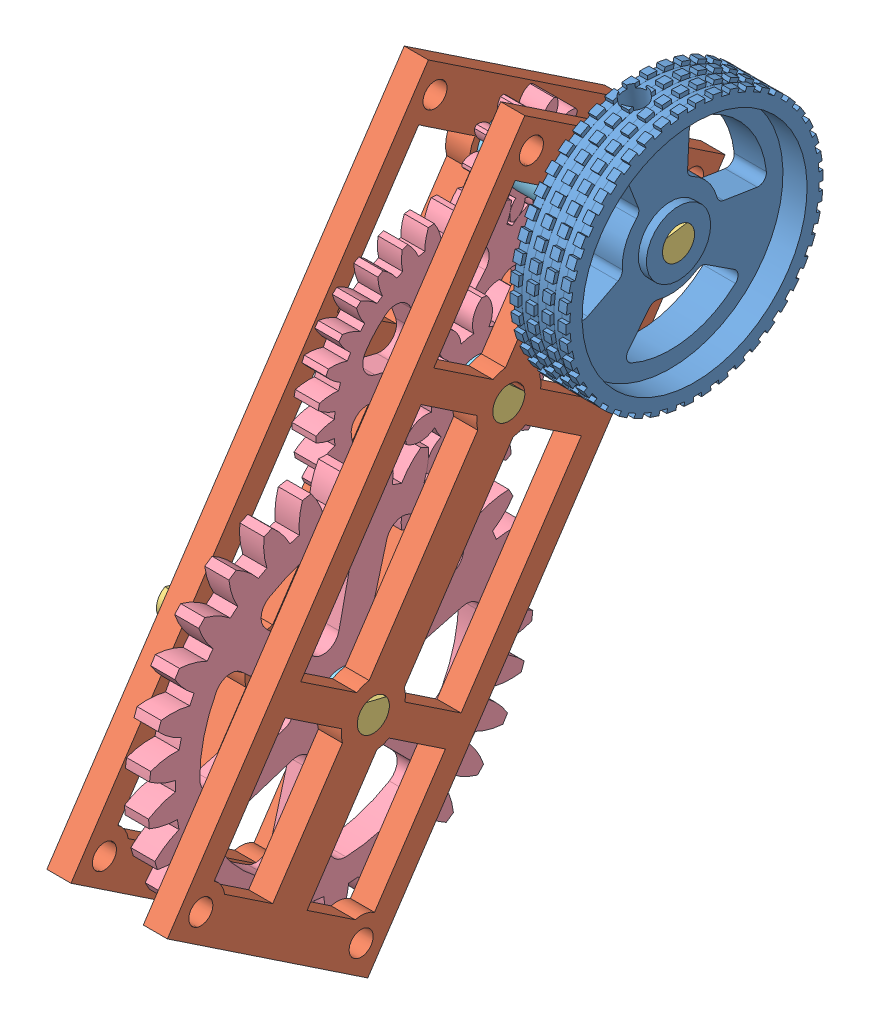
SolidWorks assembly Gearbox Assembly 2, configuration Default. Lengths in mm.
Overall size (37 89.16 75.24).
20 component instances, 5 part files, 14 mates.
Components (placement in the parent):
- knob-1: knob [Default] at (6.9201 63.2901 -12.547) x (1 0 0) z (0 -0.159161 0.987253) size (7 31.99 32)
- plate 2-1: plate 2 [Default] at (1.9201 35.0287 6.3551) x (0 -0.831219 0.555945) z (-1 0 0) size (80 30 3)
- Subassembly 1-1: Subassembly 1 [Default] at (9.8488 64.0208 -35.2482) x (0 -0.987253 -0.159161) z (-1 0 0) size (12 11.53 25)
  - axle-1: axle [25mm axle] at (-2.8918 22.5281 -2.0712) size (3.5 4 25)
  - root gear assignment-1: root gear assignment [10T 1.0Mod] at (-2.8918 22.5281 18.9288) x (-1 0 0) z (0 0 -1) size (12 11.53 3)
  - Spacer-1: Spacer [4.2-1] at (-2.8918 22.5281 18.9288) x (0.950881 0.309557 0) z (0 0 1) size (6.2 6.2 1)
  - Spacer-2: Spacer [4.2-5] at (-2.8918 22.5281 10.9288) x (-0.422504 -0.906361 0) z (0 0 1) size (6.2 6.2 5)
- Subassembly 2-1: Subassembly 2 [Default] at (-12.5765 19.149 -11.8568) x (0 0.742138 -0.670247) z (1 0 0) size (32 31.89 15)
  - root gear assignment-1: root gear assignment [30T 1.0Mod] at (13.4314 26.1825 3.4966) size (32 31.89 3)
  - root gear assignment-2: root gear assignment [10T 1.5Mod] at (13.4314 26.1825 7.4966) size (18 17.3 3)
  - axle-1: axle [15mm axle] at (13.4314 26.1825 -0.5034) x (-1 0 0) z (0 0 1) size (3.5 4 15)
  - Spacer-1: Spacer [4.2-1] at (13.4314 26.1825 10.4966) size (6.2 6.2 1)
  - Spacer-3: Spacer [4.2-1] at (13.4314 26.1825 6.4966) size (6.2 6.2 1)
  - Spacer-4: Spacer [4.2-1] at (13.4314 26.1825 2.4966) size (6.2 6.2 1)
- Subassembly3-1: Subassembly3 [Default] at (-24.9496 4.3708 -2.0102) x (0 0.971552 -0.236825) z (1 0 0) size (48 47.84 25)
  - root gear assignment-1: root gear assignment [30T 1.5Mod] at (12.467 20.9936 19.8697) size (48 47.84 3)
  - axle-1: axle [25mm axle] at (12.467 20.9936 1.8697) x (-1 0 0) z (0 0 1) size (3.5 4 25)
  - Spacer-1: Spacer [4.2-1] at (12.467 20.9936 23.8697) x (-0.923728 -0.383049 0) z (0 0 -1) size (6.2 6.2 1)
  - Spacer-2: Spacer [4.2-5] at (12.467 20.9936 14.8697) size (6.2 6.2 5)
- plate 2-2: plate 2 [Default] at (-10.0799 35.0287 6.3551) x (0 -0.831219 0.555945) z (-1 0 0) size (80 30 3)
Mates (geometry in assembly coordinates):
- Parallel1: parallel aligned: line of plate-1 through (1.9201 10.1191 41.0612) axis (0 0.831219 -0.555945); line of plate-2 through (-13.0799 10.1191 41.0612) axis (0 0.831219 -0.555945)
- Concentric3: concentric anti-aligned: cylinder of plate-1 through (1.9201 63.2901 -12.547) axis (-1 0 0) radius 2; cylinder of Subassembly 1-1/axle-1 through (-13.0799 63.2901 -12.547) axis (1 0 0) radius 2
- Concentric4: concentric anti-aligned: cylinder of Subassembly 1-1/axle-1 through (-13.0799 63.2901 -12.547) axis (1 0 0) radius 2; cylinder of plate-2 through (-10.0799 63.2901 -12.547) axis (-1 0 0) radius 2
- Coincident6: coincident aligned: plane of Subassembly 1-1/axle-1 through (-13.0799 63.2901 -12.547) normal (-1 0 0); plane of plate-2 through (-13.0799 35.0287 6.3551) normal (-1 0 0)
- Concentric5: concentric anti-aligned: cylinder of knob-1 through (6.9201 63.2901 -12.547) axis (-1 0 0) radius 2; cylinder of Subassembly 1-1/axle-1 through (-13.0799 63.2901 -12.547) axis (1 0 0) radius 2
- Coincident7: coincident aligned: plane of knob-1 through (11.9201 67.2391 -11.9104) normal (1 0 0); plane of Subassembly 1-1/axle-1 through (11.9201 63.2901 -12.547) normal (1 0 0)
- Coincident8: coincident anti-aligned: plane of plate-1 through (-1.0799 35.0287 6.3551) normal (-1 0 0); plane of Subassembly 1-1/Spacer-2 through (-1.0799 63.2901 -12.547) normal (1 0 0)
- Concentric6: concentric aligned: cylinder of Subassembly 2-1/axle-1 through (1.9201 46.6658 -1.4281) axis (-1 0 0) radius 2; cylinder of plate-2 through (-10.0799 46.6658 -1.4281) axis (-1 0 0) radius 2
- Coincident9: coincident aligned: plane of plate-1 through (1.9201 35.0287 6.3551) normal (1 0 0); plane of Subassembly 2-1/axle-1 through (1.9201 46.6658 -1.4281) normal (1 0 0)
- Concentric7: concentric aligned: cylinder of plate-1 through (1.9201 21.4549 15.4337) axis (-1 0 0) radius 2; cylinder of Subassembly3-1/axle-1 through (1.9201 21.4549 15.4337) axis (-1 0 0) radius 2
- Coincident10: coincident aligned: plane of plate-1 through (1.9201 35.0287 6.3551) normal (1 0 0); plane of Subassembly3-1/axle-1 through (1.9201 21.4549 15.4337) normal (1 0 0)
- GearMate1: gear = 15 : 45 mm: cylinder of Subassembly3-1/root gear assignment-1 through (-5.0799 21.4549 15.4337) axis (1 0 0) radius 20.625; cylinder of Subassembly 2-1/root gear assignment-2 through (-5.0799 46.6658 -1.4281) axis (1 0 0) radius 5.625
- GearMate4: gear = 10 : 30 mm: cylinder of Subassembly 2-1/root gear assignment-1 through (-9.0799 46.6658 -1.4281) axis (1 0 0) radius 13.75; cylinder of Subassembly 1-1/root gear assignment-1 through (-9.0799 63.2901 -12.547) axis (1 0 0) radius 3.75
- Parallel4: parallel aligned: plane of knob-1 through (9.8201 74.6435 -10.7167) normal (0 0.987253 0.159161); plane of Subassembly 1-1/axle-1 through (-13.0799 64.5605 -11.0022) normal (0 0.987253 0.159161)
